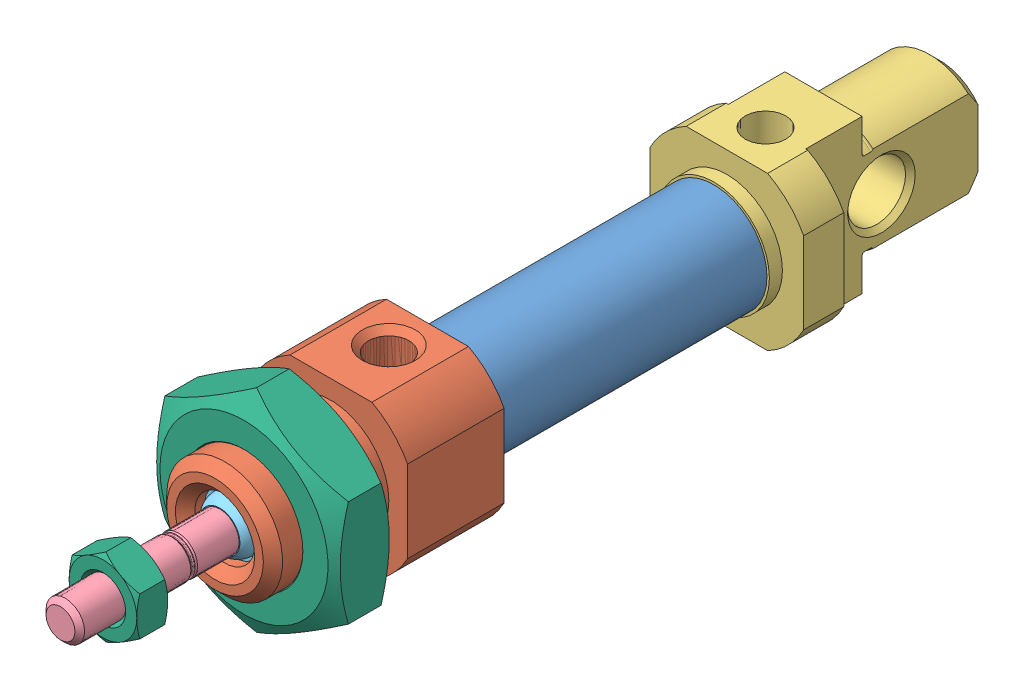
SolidWorks assembly Janatics-Default, configuration Default. Lengths in mm.
Overall size (19 21.94 91).
7 component instances, 6 part files, 17 mates.
Components (placement in the parent):
- Janatics-Default_Cylinder Barrel-1: Janatics-Default_Cylinder Barrel [1501150000] at origin size (11 11 28.3)
- Janatics-Default_Front end cover-1: Janatics-Default_Front end cover [410200] at (0 0 24) size (15.88 15.88 27)
- Janatics-Default_Rear End Cover-1: Janatics-Default_Rear End Cover [410199] at (0 0 -15.5) x (0 0 1) z (-1 0 0) size (27 15.9 15.9)
- Janatics-Default_Piston rod-1: Janatics-Default_Piston rod [101050000] at (0 0 26.5) x (0 0 1) z (0 1 0) size (64 8 8)
- Janatics-Default_Nut ring cum wiper-1: Janatics-Default_Nut ring cum wiper [641529] at (0 0 35.5) x (-0.923121 0.38451 0) z (0.38451 0.923121 0) size (9.1 4.5 9.1)
- Janatics-Default_Lock Nut-1: Janatics-Default_Lock Nut [832001] at (0 0 31.5) x (0 0 -1) z (1 0 0) size (6 21.94 19)
- Janatics-Default_Lock Nut-2: Janatics-Default_Lock Nut [830016] at (0 0 47.5) x (0 0 1) z (-1 0 0) size (3.2 8.08 7)
Mates (geometry in assembly coordinates):
- Concentric1: concentric aligned: cylinder of Janatics-Default_Cylinder Barrel-1 through (0 0 0) axis (0 0 1) radius 5; cylinder of Janatics-Default_Front end cover-1 through (0 0 24) axis (0 0 1) radius 5.05
- Coincident1: coincident aligned: plane of Janatics-Default_Front end cover-1 through (0 0 24) normal (1 0 0)
- Concentric2: concentric anti-aligned: cylinder of Janatics-Default_Cylinder Barrel-1 through (0 0 0) axis (0 0 1) radius 5; cylinder of Janatics-Default_Rear End Cover-1 through (0 0 -15.5) axis (0 0 -1) radius 5.75
- Concentric3: concentric anti-aligned: cylinder of Janatics-Default_Cylinder Barrel-1 through (0 0 0) axis (0 0 1) radius 5; cylinder of Janatics-Default_Piston rod-1 through (0 0 26.5) axis (0 0 -1) radius 2
- Coincident5: coincident anti-aligned: plane of Janatics-Default_Cylinder Barrel-1 through (0 5.5 -14.15) normal (0 0 -1); plane of Janatics-Default_Rear End Cover-1 through (0 5.75 -14.15) normal (0 0 1)
- Coincident6: coincident anti-aligned: circle of Cylinder Barrel-1; plane of Janatics-Default_Front end cover-1 through (0 5.75 14.15) normal (0 0 -1)
- Coincident7: coincident anti-aligned: plane of Janatics-Default_Rear End Cover-1 through (0 4.78 -10.5) normal (0 0 1); plane of Janatics-Default_Piston rod-1 through (0 0 -10.5) normal (0 0 -1)
- Concentric4: concentric aligned: cylinder of Janatics-Default_Piston rod-1 through (0 0 26.5) axis (0 0 -1) radius 2; cylinder of Janatics-Default_Nut ring cum wiper-1 through (0 0 35.5) axis (0 0 -1) radius 1.75
- Coincident8: coincident anti-aligned: plane of Janatics-Default_Front end cover-1 through (0 3.1 35.5) normal (0 0 -1); plane of Janatics-Default_Nut ring cum wiper-1 through (1.5957 3.831 35.5) normal (0 0 1)
- Concentric5: concentric anti-aligned: cylinder of Janatics-Default_Front end cover-1 through (0 0 24) axis (0 0 1) radius 6; cylinder of Janatics-Default_Lock Nut-1 through (0 0 28.5) axis (0 0 -1) radius 5.4
- Width1: width aligned: plane of Janatics-Default_Lock Nut-1 through (0 0 34.5) normal (0 0 1); plane of Janatics-Default_Lock Nut-1 through (0 0 28.5) normal (0 0 -1); plane of Janatics-Default_Front end cover-1 through (0 4.1 37.5) normal (0 0 1); plane of Janatics-Default_Front end cover-1 through (0 6 25.5) normal (0 0 1)
- Concentric6: concentric anti-aligned: cylinder of Janatics-Default_Piston rod-1 through (0 0 26.5) axis (0 0 -1) radius 2; cylinder of Janatics-Default_Lock Nut-2 through (0 0 49.1) axis (0 0 1) radius 1.65
- Width2: width aligned: plane of Janatics-Default_Lock Nut-2 through (0 0 49.1) normal (0 0 1); plane of Janatics-Default_Lock Nut-2 through (0 0 45.9) normal (0 0 -1); plane of Janatics-Default_Piston rod-1 through (1.9464 0 41.5) normal (0 0 1); plane of Janatics-Default_Piston rod-1 through (1.5 0 53.5) normal (0 0 1)
- Coincident9: coincident anti-aligned: plane of Janatics-Default_Rear End Cover-1 through (0 0 -15.5) normal (-1 0 0)
- Coincident10: coincident aligned: plane of Janatics-Default_Lock Nut-1 through (0 0 31.5) normal (1 0 0)
- Coincident11: coincident anti-aligned: plane of Janatics-Default_Lock Nut-2 through (0 0 47.5) normal (-1 0 0)
- Parallel1: parallel aligned: plane of Piston rod-1 through (2.5 1.6583 47.0005) normal (1 0 0); plane of Lock Nut-1 through (12 6.9282 33.5005) normal (1 0 0)
